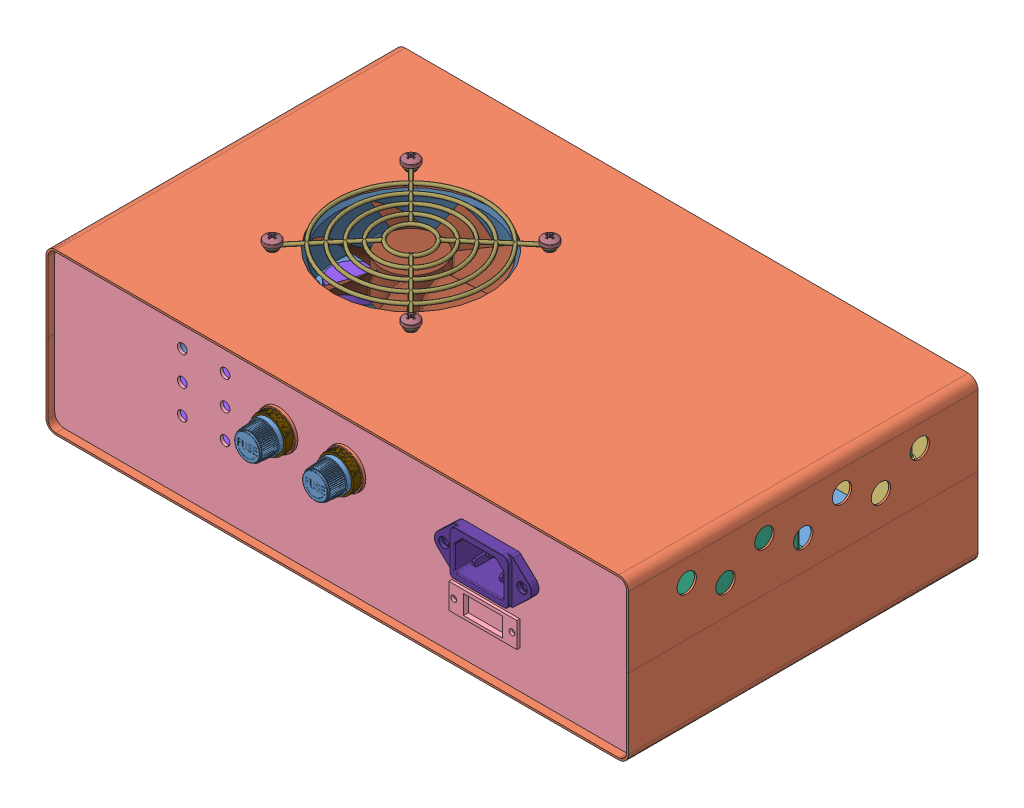
SolidWorks assembly FONTE, configuration Valor predeterminado. Lengths in mm.
Overall size (300 104.82 206.15).
57 component instances, 32 part files, 77 mates.
Components (placement in the parent):
- reforco Interno-1: reforco Interno [Valor predeterminado] at (136.2535 24.5126 213) x (-1 0 0) z (0 0 1) size (298 45 170)
- Tampa-1: Tampa [Valor predeterminado] at (-162.7465 19.8126 388) x (1 0 0) z (0 0 -1) size (300 41.3 180)
- Tampa-2: Tampa [Valor predeterminado] at (-162.7465 19.8126 208) size (300 41.3 180)
- frontal_montado-1: frontal_montado [Valor predeterminado] at (-161.7465 -19.8874 211.5) size (298 80 1.5)
- Frontal-2: Frontal [Valor predeterminado] at (-161.7465 -19.8874 383) size (298 80 1.5)
- sapata-1: sapata [Valor predeterminado] at (107.2535 -37.9874 233) size (17 16.5 17)
- sapata-2: sapata [Valor predeterminado] at (-12.7465 -37.9874 298) size (17 16.5 17)
- sapata-3: sapata [Valor predeterminado] at (-132.7465 -37.9874 233) size (17 16.5 17)
- sapata-4: sapata [Valor predeterminado] at (107.2535 -37.9874 363) size (17 16.5 17)
- sapata-5: sapata [Valor predeterminado] at (-132.7465 -37.9874 363) size (17 16.5 17)
- 16x2 LCD Display-1: 16x2 LCD Display [Default] at (71.2535 29.5626 213) x (1 0 0) z (0 1 0) size (80.1 19.3 36.1)
- Banana Connector - 4.00mm - Short - Green-1: Banana Connector - 4.00mm - Short - Green [Valor predeterminado] at (-51.7465 0.1126 211.754) x (-1 0 0) z (0 0 -1) size (13.54 19.33 14.94)
- Banana Connector - 4.00mm - Short - Blue-1: Banana Connector - 4.00mm - Short - Blue [Valor predeterminado] at (-31.7465 0.1126 211.754) x (-1 0 0) z (0 0 -1) size (13.54 19.33 14.94)
- Banana Connector - 4.00mm - Short - Red-1: Banana Connector - 4.00mm - Short - Red [Valor predeterminado] at (8.2535 0.1126 211.754) x (-1 0 0) z (0 0 -1) size (13.54 19.33 14.94)
- Banana Connector - 4.00mm - Short - Yellow-1: Banana Connector - 4.00mm - Short - Yellow [Valor predeterminado] at (-71.7465 0.1126 211.754) x (-1 0 0) z (0 0 -1) size (13.54 19.33 14.94)
- Banana Connector - 4.00mm - Short - Black-1: Banana Connector - 4.00mm - Short - Black [Valor predeterminado] at (28.2535 0.1126 211.754) x (-1 0 0) z (0 0 -1) size (13.54 19.33 14.94)
- Switch-1: Switch [Varsayılan] at (-131.7265 38.5976 211.5) x (0 0 -1) z (1 0 0) size (18.35 15.52 10.6)
- led holder-1: led holder [Default] at (5.2535 40.1126 211.5) x (-0.383049 0.923728 0) z (-0.923728 -0.383049 0) size (10 9.5 10)
- led holder-2: led holder [Default] at (-14.7465 40.1126 211.5) x (-0.923728 -0.383049 0) z (0.383049 -0.923728 0) size (10 9.5 10)
- led holder-3: led holder [Default] at (-34.7465 40.1126 211.5) x (-0.923728 -0.383049 0) z (0.383049 -0.923728 0) size (10 9.5 10)
- LED_THT_3D_GREEN-2: LED_THT_3D_GREEN [Default] at (5.2535 40.1126 210) x (-1 0 0) z (0 0 -1) size (3.73 4 9)
- LED_THT_3D_YELLOW-3: LED_THT_3D_YELLOW [Default] at (-14.7465 40.1126 210) x (-1 0 0) z (0 0 -1) size (3.73 4 9)
- LED_THT_3D_RED-2: LED_THT_3D_RED [Default] at (-34.7465 40.1126 210) x (-1 0 0) z (0 0 -1) size (3.73 4 9)
- TOMADA FÊMEA-1: TOMADA FÊMEA [Valor predeterminado] at (62.7535 30.8626 371.5) size (50 23.06 28.8)
- 10A 250VAC Fuse Holder-1: 10A 250VAC Fuse Holder [Valor predeterminado] at (-11.4298 35.1126 390) x (0 0 -1) z (1 0 0) size (51.45 19.92 19.75)
  - SF372 10A 250VAC Fuse Holder.STEP-1: SF372 10A 250VAC Fuse Holder.STEP [Valor predeterminado] at origin size (51.45 19.92 19.75)
    - SF372 - Body.STEP-1: SF372 - Body.STEP [Valor predeterminado] at origin size (40.6 18.15 18)
    - SF372 - Cap.STEP-1: SF372 - Cap.STEP [Valor predeterminado] at (1.2 0 0) size (16.25 16 16)
    - SF372 - Nylon Washer.STEP-1: SF372 - Nylon Washer.STEP [Valor predeterminado] at (5.5 0 0) x (-1 0 0) z (0 0 -1) size (1.5 19.75 19.75)
    - SF372 - Nylon Washer.STEP-2: SF372 - Nylon Washer.STEP [Valor predeterminado] at (7.8875 0 0) size (1.5 19.75 19.75)
    - SF372 - Nut.STEP-1: SF372 - Nut.STEP [Valor predeterminado] at (9.3875 0 0) size (2.6 19.92 17.26)
- 10A 250VAC Fuse Holder-2: 10A 250VAC Fuse Holder [Valor predeterminado] at (-46.4298 35.1126 390) x (0 0 -1) z (1 0 0) size (51.45 19.92 19.75)
  - SF372 10A 250VAC Fuse Holder.STEP-1: SF372 10A 250VAC Fuse Holder.STEP [Valor predeterminado] at origin size (51.45 19.92 19.75)
    - SF372 - Body.STEP-1: SF372 - Body.STEP [Valor predeterminado] at origin size (40.6 18.15 18)
    - SF372 - Cap.STEP-1: SF372 - Cap.STEP [Valor predeterminado] at (1.2 0 0) size (16.25 16 16)
    - SF372 - Nylon Washer.STEP-1: SF372 - Nylon Washer.STEP [Valor predeterminado] at (5.5 0 0) x (-1 0 0) z (0 0 -1) size (1.5 19.75 19.75)
    - SF372 - Nylon Washer.STEP-2: SF372 - Nylon Washer.STEP [Valor predeterminado] at (7.8875 0 0) size (1.5 19.75 19.75)
    - SF372 - Nut.STEP-1: SF372 - Nut.STEP [Valor predeterminado] at (9.3875 0 0) size (2.6 19.92 17.26)
- Chave HH-1: Chave HH [Valor predeterminado] at (77.7535 -0.4874 386) x (-1 0 0) z (0 0 -1) size (35 13 10)
- EC11_rotary_encoder_knob-1: EC11_rotary_encoder_knob [Valor predeterminado] at (-61.7465 25.1126 211.5) x (1 0 0) z (0 1 0) size (15.6 16.8 15.6)
- EC11_rotary_encoder_knob-2: EC11_rotary_encoder_knob [Valor predeterminado] at (-91.7465 25.1126 211.5) x (0 1 0) z (-1 0 0) size (15.6 16.8 15.6)
- trafo 3A-1: trafo 3A [Valor predeterminado] at (71.2535 -19.4874 343) size (58 66.5 108)
- trafo 1A-1: trafo 1A [Valor predeterminado] at (11.2535 -19.4874 358) size (38 50 88)
- placa_F_var-1: placa_F_var [Valor predeterminado] at (-75.7465 -16.4874 363) x (0 0 -1) z (1 0 0) size (90 45.5 76)
- placa_F_fix-1: placa_F_fix [Valor predeterminado] at (-10.7465 -16.4874 363) x (0 0 -1) z (1 0 0) size (110 41.5 50)
- 80 FanCooler-A-1: 80 FanCooler-A [Valor predeterminado] at (-66.7465 35.1126 296) size (152.62 38.02 152.62)
  - 80 FanCooler-Frame-1: 80 FanCooler-Frame [Valor predeterminado] at origin size (80 27 80)
  - 80 FanCooler-Fan-1: 80 FanCooler-Fan [Valor predeterminado] at (0 14.5 0) x (0.4333 0 0.90125) z (-0.90125 0 0.4333) size (77.79 20.07 78.2)
  - 80FanCooler-Guard-1: 80FanCooler-Guard [Valor predeterminado] at (0 26.9 0) x (0.707107 0 0.707107) z (-0.707107 0 0.707107) size (107.92 3.98 107.92)
  - DIN EN ISO 7045 - M4 x 35 - Z - 35N-1: DIN EN ISO 7045 - M4 x 35 - Z - 35N [Valor predeterminado] at (35.75 31.8 -35.75) x (0 -1 0) z (-0.999963 0 -0.008587) size (38.02 8 8)
  - DIN EN ISO 7045 - M4 x 35 - Z - 35N-2: DIN EN ISO 7045 - M4 x 35 - Z - 35N [Valor predeterminado] at (-35.75 31.8 -35.75) x (0 -1 0) z (-0.008587 0 0.999963) size (38.02 8 8)
  - DIN EN ISO 7045 - M4 x 35 - Z - 35N-3: DIN EN ISO 7045 - M4 x 35 - Z - 35N [Valor predeterminado] at (-35.75 31.8 35.75) x (0 -1 0) z (0.999963 0 0.008587) size (38.02 8 8)
  - DIN EN ISO 7045 - M4 x 35 - Z - 35N-4: DIN EN ISO 7045 - M4 x 35 - Z - 35N [Valor predeterminado] at (35.75 31.8 35.75) x (0 -1 0) z (0.008587 0 -0.999963) size (38.02 8 8)
  - DIN EN ISO 10511 - M4 - N-1: DIN EN ISO 10511 - M4 - N [Valor predeterminado] at (-36 -1.95 -36) x (1 0 0) z (0 -1 0) size (7 8.08 5)
  - DIN EN ISO 10511 - M4 - N-2: DIN EN ISO 10511 - M4 - N [Valor predeterminado] at (36 -1.95 36) x (-1 0 0) z (0 -1 0) size (7 8.08 5)
  - DIN EN ISO 10511 - M4 - N-3: DIN EN ISO 10511 - M4 - N [Valor predeterminado] at (36 -1.95 -36) x (0 0 1) z (0 -1 0) size (7 8.08 5)
  - DIN EN ISO 10511 - M4 - N-4: DIN EN ISO 10511 - M4 - N [Valor predeterminado] at (-36 -1.95 36) x (0 0 -1) z (0 -1 0) size (7 8.08 5)
Mates (geometry in assembly coordinates):
- Coincidente1: coincident anti-aligned: plane of reforco Interno-1 through (-161.7465 24.5126 383) normal (-1 0 0); plane of Tampa-1 through (-161.7465 19.8126 208) normal (1 0 0)
- Coincidente2: coincident anti-aligned: plane of reforco Interno-1 through (-156.7465 -20.4874 383) normal (0 -1 0); plane of Tampa-1 through (-157.7465 -20.4874 208) normal (0 1 0)
- Distância1: distance = 5 mm aligned: plane of reforco Interno-1 through (131.2535 -15.4874 383) normal (0 0 1); plane of Tampa-1 through (-157.7465 -16.4874 388) normal (0 0 1)
- Coincidente4: coincident anti-aligned: plane of reforco Interno-1 through (136.2535 24.5126 383) normal (1 0 0); plane of Tampa-2 through (136.2535 19.8126 388) normal (-1 0 0)
- Coincidente5: coincident anti-aligned: plane of Tampa-1 through (136.2535 19.8126 208) normal (0 1 0); plane of Tampa-2 through (136.2535 19.8126 388) normal (0 -1 0)
- Coincidente6: coincident aligned: plane of Tampa-1 through (-157.7465 -16.4874 208) normal (0 0 -1); plane of Tampa-2 through (-157.7465 56.1126 208) normal (0 0 -1)
- Coincidente7: coincident anti-aligned: plane of Tampa-2 through (136.2535 19.8126 388) normal (-1 0 0); plane of Frontal-1 through (136.2535 -14.8874 213) normal (1 0 0)
- Coincidente8: coincident anti-aligned: plane of Tampa-2 through (-157.7465 60.1126 388) normal (0 -1 0); plane of Frontal-1 through (-156.7465 60.1126 213) normal (0 1 0)
- Coincidente9: coincident anti-aligned: plane of reforco Interno-1 through (131.2535 -15.4874 213) normal (0 0 -1); plane of Frontal-1 through (-156.7465 55.1126 213) normal (0 0 1)
- Coincidente10: coincident anti-aligned: plane of reforco Interno-1 through (131.2535 -15.4874 383) normal (0 0 1); plane of Frontal-2 through (-156.7465 55.1126 383) normal (0 0 -1)
- Coincidente11: coincident anti-aligned: plane of Tampa-2 through (-161.7465 19.8126 388) normal (1 0 0); plane of Frontal-2 through (-161.7465 -14.8874 384.5) normal (-1 0 0)
- Coincidente12: coincident anti-aligned: plane of Tampa-2 through (-157.7465 60.1126 388) normal (0 -1 0); plane of Frontal-2 through (-156.7465 60.1126 384.5) normal (0 1 0)
- Concêntrico2: concentric anti-aligned: circle of Tampa-1; circle of sapata-1
- Coincidente14: coincident anti-aligned: plane of Tampa-1 through (-157.7465 -21.4874 208) normal (0 -1 0); circle of sapata-1
- Coincidente15: coincident anti-aligned: plane of Tampa-1 through (-157.7465 -21.4874 208) normal (0 -1 0); plane of sapata-3 through (-132.7465 -21.4874 233) normal (0 1 0)
- Coincidente16: coincident anti-aligned: plane of Tampa-1 through (-157.7465 -21.4874 208) normal (0 -1 0); plane of sapata-2 through (-12.7465 -21.4874 298) normal (0 1 0)
- Concêntrico3: concentric anti-aligned: circle of Tampa-1; circle of sapata-3
- Coincidente17: coincident anti-aligned: plane of Tampa-1 through (-157.7465 -21.4874 208) normal (0 -1 0); plane of sapata-5 through (-132.7465 -21.4874 363) normal (0 1 0)
- Coincidente18: coincident anti-aligned: plane of Tampa-1 through (-157.7465 -21.4874 208) normal (0 -1 0); plane of sapata-4 through (107.2535 -21.4874 363) normal (0 1 0)
- Concêntrico4: concentric aligned: circle of Tampa-1; circle of sapata-4
- Concêntrico5: concentric aligned: circle of Tampa-1; circle of sapata-5
- Concêntrico6: concentric aligned: circle of Tampa-1; circle of sapata-2
- Distância2: distance = 0.45 mm anti-aligned: plane of 16x2 LCD Display-1 through (106.8035 41.6626 207) normal (1 0 0); plane of Frontal-1 through (107.2535 42.1126 213) normal (-1 0 0)
- Distância3: distance = 0.45 mm anti-aligned: plane of 16x2 LCD Display-1 through (106.8035 41.6626 207) normal (0 1 0); plane of Frontal-1 through (107.2535 42.1126 213) normal (0 -1 0)
- Coincidente22: coincident anti-aligned: plane of Frontal-1 through (-156.7465 55.1126 213) normal (0 0 1); plane of 16x2 LCD Display-1 through (71.2535 29.5626 213) normal (0 0 -1)
- Concêntrico7: concentric aligned: circle of Frontal-1; circle of Banana Connector - 4.00mm - Short - Black-1
- Coincidente24: coincident anti-aligned: plane of Frontal-1 through (-156.7465 55.1126 211.5) normal (0 0 -1); plane of Banana Connector - 4.00mm - Short - Black-1 through (28.2535 0.1126 211.5) normal (0 0 1)
- Coincidente25: coincident anti-aligned: plane of Frontal-1 through (-156.7465 55.1126 211.5) normal (0 0 -1); plane of Banana Connector - 4.00mm - Short - Red-1 through (8.2535 0.1126 211.5) normal (0 0 1)
- Concêntrico8: concentric aligned: circle of Frontal-1; circle of Banana Connector - 4.00mm - Short - Red-1
- Coincidente26: coincident anti-aligned: plane of Frontal-1 through (-156.7465 55.1126 211.5) normal (0 0 -1); plane of Banana Connector - 4.00mm - Short - Green-1 through (-51.7465 0.1126 211.5) normal (0 0 1)
- Coincidente27: coincident anti-aligned: plane of Frontal-1 through (-156.7465 55.1126 211.5) normal (0 0 -1); plane of Banana Connector - 4.00mm - Short - Yellow-1 through (-71.7465 0.1126 211.5) normal (0 0 1)
- Concêntrico9: concentric aligned: circle of Frontal-1; circle of Banana Connector - 4.00mm - Short - Green-1
- Concêntrico10: concentric aligned: circle of Frontal-1; circle of Banana Connector - 4.00mm - Short - Yellow-1
- Concêntrico11: concentric aligned: circle of Frontal-1; circle of Banana Connector - 4.00mm - Short - Blue-1
- Coincidente28: coincident anti-aligned: plane of Frontal-1 through (-156.7465 55.1126 211.5) normal (0 0 -1); plane of Banana Connector - 4.00mm - Short - Blue-1 through (-31.7465 0.1126 211.5) normal (0 0 1)
- Coincidente29: coincident anti-aligned: plane of Frontal-1 through (-156.7465 55.1126 211.5) normal (0 0 -1); plane of Switch-1 through (-131.7265 38.5976 211.5) normal (0 0 1)
- Distância4: distance = 0.45 mm anti-aligned: plane of Switch-1 through (-127.1965 32.5626 220.41) normal (0 -1 0); plane of Frontal-1 through (-126.7465 32.1126 213) normal (0 1 0)
- Distância5: distance = 0.45 mm anti-aligned: plane of Switch-1 through (-127.1965 32.5626 220.41) normal (1 0 0); plane of Frontal-1 through (-126.7465 45.1126 213) normal (-1 0 0)
- Coincidente30: coincident anti-aligned: plane of Frontal-1 through (-156.7465 55.1126 211.5) normal (0 0 -1); plane of led holder-1 through (5.2535 40.1126 211.5) normal (0 0 1)
- Coincidente31: coincident anti-aligned: plane of Frontal-1 through (-156.7465 55.1126 211.5) normal (0 0 -1); plane of led holder-2 through (-14.7465 40.1126 211.5) normal (0 0 1)
- Coincidente32: coincident anti-aligned: plane of Frontal-1 through (-156.7465 55.1126 211.5) normal (0 0 -1); plane of led holder-3 through (-34.7465 40.1126 211.5) normal (0 0 1)
- Concêntrico12: concentric aligned: cylinder of Frontal-1; cylinder of led holder-1 through (5.2535 40.1126 217.5) axis (0 0 -1) radius 3.8
- Concêntrico13: concentric aligned: cylinder of Frontal-1 through (-14.7465 40.1126 213) axis (0 0 -1) radius 4; cylinder of led holder-2 through (-14.7465 40.1126 217.5) axis (0 0 -1) radius 3.8
- Concêntrico14: concentric aligned: cylinder of Frontal-1 through (-34.7465 40.1126 213) axis (0 0 -1) radius 4; cylinder of led holder-3 through (-34.7465 40.1126 217.5) axis (0 0 -1) radius 3.8
- Coincidente34: coincident anti-aligned: circle of led holder-1; plane of LED_THT_3D_GREEN-2 through (5.2535 40.1126 210) normal (0 0 1)
- Concêntrico16: concentric anti-aligned: circle of led holder-1; circle of LED_THT_3D_GREEN-2
- Coincidente35: coincident anti-aligned: circle of led holder-2; plane of LED_THT_3D_YELLOW-3 through (-14.7465 40.1126 210) normal (0 0 1)
- Concêntrico17: concentric anti-aligned: circle of led holder-2; circle of LED_THT_3D_YELLOW-3
- Coincidente36: coincident anti-aligned: circle of led holder-3; plane of LED_THT_3D_RED-2 through (-34.7465 40.1126 210) normal (0 0 1)
- Concêntrico18: concentric anti-aligned: circle of led holder-3; cylinder of LED_THT_3D_RED-2 through (-34.7465 40.1126 209) axis (0 0 1) radius 2
- Coincidente37: coincident anti-aligned: plane of Frontal-2 through (-156.7465 55.1126 384.5) normal (0 0 1); plane of TOMADA FÊMEA-1 through (62.7535 30.8626 384.5) normal (0 0 -1)
- Coincidente38: coincident anti-aligned: plane of Frontal-2 through (46.2535 40.1126 383) normal (0 -1 0); plane of TOMADA FÊMEA-1 through (71.7535 40.1126 371.5) normal (0 1 0)
- Coincidente39: coincident anti-aligned: plane of Frontal-2 through (76.2535 40.1126 383) normal (-1 0 0); plane of TOMADA FÊMEA-1 through (76.2535 21.6126 371.5) normal (1 0 0)
- Coincidente40: coincident anti-aligned: plane of Frontal-2 through (-156.7465 55.1126 384.5) normal (0 0 1); plane of 10A 250VAC Fuse Holder-2/SF372 10A 250VAC Fuse Holder.STEP-1/SF372 - Nylon Washer.STEP-1 through (-46.4298 35.1126 384.5) normal (0 0 -1)
- Concêntrico19: concentric anti-aligned: circle of Frontal-2; circle of 10A 250VAC Fuse Holder-2/SF372 10A 250VAC Fuse Holder.STEP-1/SF372 - Body.STEP-1
- Coincidente41: coincident anti-aligned: plane of Frontal-2 through (-156.7465 55.1126 384.5) normal (0 0 1); plane of 10A 250VAC Fuse Holder-1/SF372 10A 250VAC Fuse Holder.STEP-1/SF372 - Nylon Washer.STEP-1 through (-11.4298 35.1126 384.5) normal (0 0 -1)
- Concêntrico20: concentric anti-aligned: circle of Frontal-2; circle of 10A 250VAC Fuse Holder-1/SF372 10A 250VAC Fuse Holder.STEP-1/SF372 - Body.STEP-1
- Coincidente44: coincident anti-aligned: plane of Frontal-2 through (49.2535 12.5126 374.5) normal (0 -1 0); plane of Chave HH-1 through (77.7535 12.5126 384.5) normal (0 1 0)
- Coincidente45: coincident anti-aligned: plane of Frontal-2 through (71.2535 -0.4874 374.5) normal (-1 0 0); plane of Chave HH-1 through (71.2535 12.5126 376) normal (1 0 0)
- Coincidente46: coincident anti-aligned: plane of Frontal-2 through (-156.7465 55.1126 384.5) normal (0 0 1); plane of Chave HH-1 through (77.7535 -0.4874 384.5) normal (0 0 -1)
- Concêntrico21: concentric aligned: circle of Frontal-1; circle of EC11_rotary_encoder_knob-1
- Concêntrico22: concentric aligned: circle of Frontal-1; circle of EC11_rotary_encoder_knob-2
- Coincidente48: coincident anti-aligned: plane of reforco Interno-1 through (-156.7465 -19.4874 383) normal (0 1 0); plane of trafo 3A-1 through (71.2535 -19.4874 343) normal (0 -1 0)
- Distância6: distance = 40 mm anti-aligned: plane of trafo 3A-1 through (71.2535 47.0126 343) normal (0 0 1); plane of Frontal-2 through (-156.7465 55.1126 383) normal (0 0 -1)
- Distância7: distance = 20 mm anti-aligned: plane of trafo 3A-1 through (115.2535 -19.4874 343) normal (1 0 0); plane of reforco Interno-1 through (135.2535 24.5126 383) normal (-1 0 0)
- Coincidente51: coincident: plane of reforco Interno-1 through (-156.7465 -19.4874 383) normal (0 1 0); line of trafo 1A-1 through (11.2535 -19.4874 294) axis (0 0 1)
- Distância8: distance = 25 mm anti-aligned: plane of trafo 1A-1 through (11.2535 30.5126 358) normal (0 0 1); plane of Frontal-2 through (-156.7465 55.1126 383) normal (0 0 -1)
- Distância9: distance = 16 mm anti-aligned: plane of trafo 1A-1 through (41.2535 -19.4874 358) normal (1 0 0); plane of trafo 3A-1 through (57.2535 -19.4874 343) normal (-1 0 0)
- Distância10: distance = 3 mm anti-aligned: plane of placa_F_var-1 through (-75.7465 -16.4874 363) normal (0 -1 0); plane of reforco Interno-1 through (-156.7465 -19.4874 383) normal (0 1 0)
- Distância11: distance = 20 mm: line of placa_F_var-1 through (-145.7465 -14.9874 363) axis (1 0 0); plane of Frontal-2 through (-156.7465 55.1126 383) normal (0 0 -1)
- Distância12: distance = 15 mm: line of placa_F_var-1 through (-145.7465 -14.9874 273) axis (0 0 1); plane of reforco Interno-1 through (-160.7465 24.5126 383) normal (1 0 0)
- Coincidente59: coincident aligned: plane of placa_F_var-1 through (-75.7465 -16.4874 363) normal (0 -1 0); plane of placa_F_fix-1 through (-10.7465 -16.4874 363) normal (0 -1 0)
- Coincidente60: coincident aligned: plane of placa_F_var-1 through (-75.7465 -14.9874 363) normal (0 0 1); plane of placa_F_fix-1 through (-10.7465 -14.9874 363) normal (0 0 1)
- Distância13: distance = 15 mm anti-aligned: plane of placa_F_fix-1 through (-60.7465 -14.9874 363) normal (-1 0 0); plane of placa_F_var-1 through (-75.7465 -14.9874 363) normal (1 0 0)
- Coincidente61: coincident anti-aligned: plane of Tampa-2 through (-157.7465 60.1126 388) normal (0 -1 0); plane of 80 FanCooler-A-1/80 FanCooler-Frame-1 through (11.2535 60.1126 296) normal (0 1 0)
- Distância14: distance = 55 mm anti-aligned: plane of 80 FanCooler-A-1/80 FanCooler-Frame-1 through (-106.7465 60.1126 336) normal (-1 0 0); plane of Tampa-2 through (-161.7465 19.8126 388) normal (1 0 0)
- Distância15: distance = 47 mm: plane of 80 FanCooler-A-1/80 FanCooler-Frame-1 through (-26.7465 60.1126 336) normal (0 0 1); line of Frontal-2 through (131.2535 60.1126 383) axis (-1 0 0)
